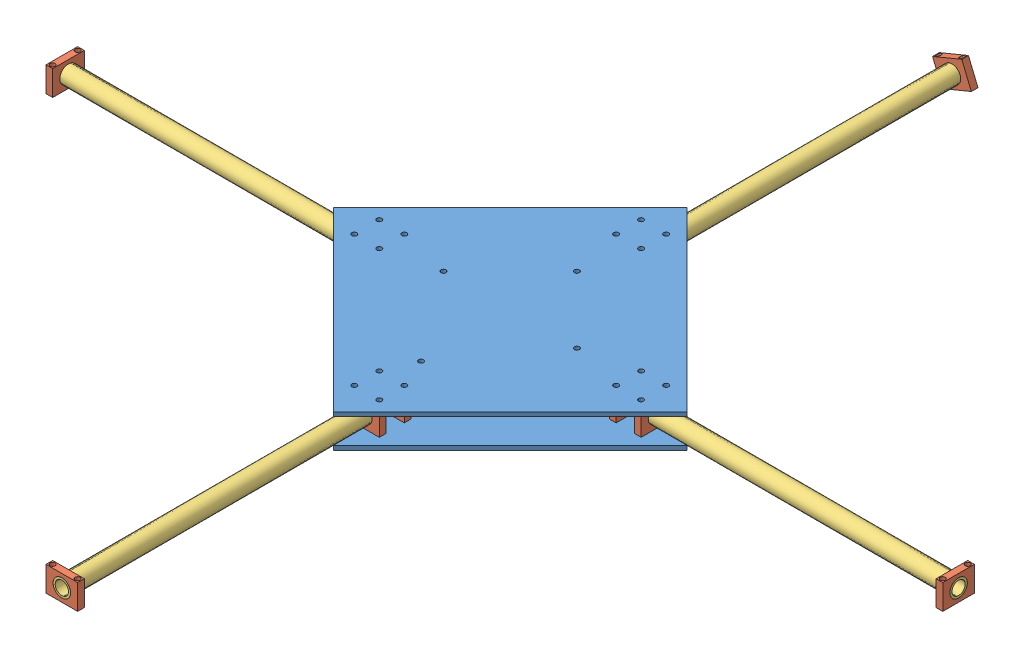
SolidWorks assembly new_drone_full_body_1, configuration Default. Lengths in mm.
Overall size (538.13 21.13 538.13).
18 component instances, 3 part files, 80 mates.
Components (placement in the parent):
- base-plate_drone_new-1: base-plate_drone_new [Default] at (-94378.7064 -1163.9739 82221.6136) size (212.13 2.5 212.15)
- holder-1: holder [Default] at (71.6083 102.2761 266.6718) x (1 0 0) z (0 1 0) size (19 4 15)
- holder-2: holder [Default] at (71.5935 87.2761 247.6718) x (1 0 0) z (0 -1 0) size (19 4 15)
- holder-4: holder [Default] at (12.0275 87.2761 169.1058) x (0 0 1) z (0 -1 0) size (19 4 15)
- holder-6: holder [Default] at (-6.9728 87.2761 188.1203) x (0.00014 0 -1) z (0 -1 0) size (19 4 15)
- holder-7: holder [Default] at (90.5787 102.2761 90.5398) x (-1 0 0) z (0 1 0) size (19 4 15)
- holder-8: holder [Default] at (71.5935 87.2761 105.5398) x (1 0 0) z (0 -1 0) size (19 4 15)
- holder-9: holder [Default] at (165.1595 102.2761 169.091) x (0 0 1) z (0 1 0) size (19 4 15)
- holder-10: holder [Default] at (150.1595 87.2761 188.1058) x (0 0 -1) z (0 -1 0) size (19 4 15)
- New_arm-1: New_arm [Default] at (350.1595 94.7761 178.6058) x (0 0 1) z (1 0 0) size (10.5 10.5 200)
- New_arm-2: New_arm [Default] at (81.0935 94.7761 109.5398) size (10.5 10.5 200)
- New_arm-3: New_arm [Default] at (12.0275 94.7761 178.6058) x (0 0.007654 -0.999971) z (1 0 0) size (10.5 10.5 200)
- New_arm-4: New_arm [Default] at (81.0935 94.7761 447.6718) size (10.5 10.5 200)
- base-plate_drone_new-2: base-plate_drone_new [Default] at (-94378.7064 -1146.4739 82221.6136) size (212.13 2.5 212.15)
- holder-11: holder [Default] at (69.4452 98.0651 -86.4602) x (0.923728 0.383049 0) z (-0.383049 0.923728 0) size (19 4 15)
- holder-12: holder [Default] at (-187.9725 102.2761 169.1058) x (0 0 1) z (0 1 0) size (19 4 15)
- holder-13: holder [Default] at (90.5935 102.2761 443.6718) x (-1 0 0) z (0 1 0) size (19 4 15)
- holder-14: holder [Default] at (346.1595 102.2761 169.1058) x (0 0 1) z (0 1 0) size (19 4 15)
Mates (geometry in assembly coordinates):
- Coincident6: coincident: circle of base-plate_drone_new-1; circle of holder-1
- Concentric1: concentric: circle of base-plate_drone_new-1; circle of holder-1
- Coincident8: coincident: circle of base-plate_drone_new-1; circle of holder-2
- Coincident9: coincident: circle of base-plate_drone_new-1; circle of holder-2
- Coincident16: coincident: circle of base-plate_drone_new-1; circle of holder-4
- Coincident17: coincident: circle of base-plate_drone_new-1; circle of holder-4
- Coincident20: coincident: circle of base-plate_drone_new-1; circle of holder-6
- Parallel2: parallel: cylinder of base-plate_drone_new-1 through (-4.9725 87.2761 171.1058) axis (0 -1 0) radius 1.5; cylinder of holder-6 through (-4.9704 102.2761 171.1206) axis (0 -1 0) radius 1.5
- Coincident22: coincident: circle of base-plate_drone_new-1; circle of holder-7
- Parallel3: parallel: cylinder of base-plate_drone_new-1 through (88.5935 87.2761 92.5398) axis (0 -1 0) radius 1.5; cylinder of holder-7 through (88.5787 87.2761 92.5398) axis (0 1 0) radius 1.5
- Coincident24: coincident: circle of base-plate_drone_new-1; circle of holder-8
- Coincident25: coincident: circle of base-plate_drone_new-1; circle of holder-8
- Coincident27: coincident: circle of base-plate_drone_new-1; circle of holder-9
- Parallel5: parallel: cylinder of base-plate_drone_new-1 through (167.1595 87.2761 186.1058) axis (0 -1 0) radius 1.5; cylinder of holder-9 through (167.1595 87.2761 186.091) axis (0 1 0) radius 1.5
- Coincident28: coincident: circle of base-plate_drone_new-1; circle of holder-10
- Coincident29: coincident: circle of base-plate_drone_new-1; circle of holder-10
- Concentric11: concentric: cylinder of holder-4 through (8.0275 94.7761 178.6058) axis (1 0 0) radius 5.25; cylinder of New_arm-3 through (-187.9725 94.7761 178.6058) axis (1 0 0) radius 5.25
- Coincident30: coincident: plane of holder-4 through (12.0275 87.2761 169.1058) normal (1 0 0); plane of New_arm-3 through (12.0275 94.7761 178.6058) normal (1 0 0)
- Concentric12: concentric: cylinder of holder-8 through (81.0935 94.7761 109.5398) axis (0 0 -1) radius 5.25; cylinder of New_arm-2 through (81.0935 94.7761 -90.4602) axis (0 0 1) radius 5.25
- Coincident31: coincident: plane of holder-8 through (71.5935 87.2761 109.5398) normal (0 0 1); plane of New_arm-2 through (81.0935 94.7761 109.5398) normal (0 0 1)
- Concentric13: concentric: cylinder of holder-2 through (81.0935 94.7761 251.6718) axis (0 0 -1) radius 5.25; cylinder of New_arm-4 through (81.0935 94.7761 247.6718) axis (0 0 1) radius 5.25
- Coincident32: coincident: plane of holder-2 through (71.5935 87.2761 247.6718) normal (0 0 -1); plane of New_arm-4 through (81.0935 94.7761 247.6718) normal (0 0 -1)
- Concentric14: concentric: cylinder of holder-10 through (154.1595 94.7761 178.6058) axis (-1 0 0) radius 5.25; cylinder of New_arm-1 through (150.1595 94.7761 178.6058) axis (1 0 0) radius 5.25
- Coincident33: coincident: plane of holder-10 through (150.1595 87.2761 188.1058) normal (-1 0 0); plane of New_arm-1 through (150.1595 94.7761 178.6058) normal (-1 0 0)
- Coincident34: coincident: circle of holder-7; circle of base-plate_drone_new-2
- Parallel6: parallel: cylinder of holder-7 through (88.5787 87.2761 92.5398) axis (0 1 0) radius 1.5; cylinder of base-plate_drone_new-2 through (88.5935 104.7761 92.5398) axis (0 -1 0) radius 1.5
- Coincident36: coincident: circle of holder-8; circle of base-plate_drone_new-2
- Parallel7: parallel: cylinder of holder-8 through (73.5935 102.2761 107.5398) axis (0 -1 0) radius 1.5; cylinder of base-plate_drone_new-2 through (73.5935 104.7761 107.5398) axis (0 -1 0) radius 1.5
- Coincident37: coincident: circle of holder-8; circle of base-plate_drone_new-2
- Parallel8: parallel: cylinder of holder-9 through (167.1595 87.2761 186.091) axis (0 1 0) radius 1.5; cylinder of base-plate_drone_new-2 through (167.1595 104.7761 186.1058) axis (0 -1 0) radius 1.5
- Parallel9: parallel: cylinder of holder-9 through (167.1595 87.2761 171.091) axis (0 1 0) radius 1.5; cylinder of base-plate_drone_new-2 through (167.1595 104.7761 171.091) axis (0 -1 0) radius 1.5
- Parallel10: parallel: cylinder of holder-10 through (152.1595 102.2761 171.1058) axis (0 -1 0) radius 1.5; cylinder of base-plate_drone_new-2 through (152.1595 104.7761 171.1058) axis (0 -1 0) radius 1.5
- Parallel11: parallel: cylinder of holder-10 through (152.1595 102.2761 186.1058) axis (0 -1 0) radius 1.5; cylinder of base-plate_drone_new-2 through (152.1595 104.7761 186.1058) axis (0 -1 0) radius 1.5
- Parallel12: parallel: cylinder of holder-1 through (88.6083 87.2761 264.6718) axis (0 1 0) radius 1.5; cylinder of base-plate_drone_new-2 through (88.6083 104.7761 264.6718) axis (0 -1 0) radius 1.5
- Parallel13: parallel: cylinder of holder-2 through (88.5935 102.2761 249.6718) axis (0 -1 0) radius 1.5; cylinder of base-plate_drone_new-2 through (88.5935 104.7761 249.6718) axis (0 -1 0) radius 1.5
- Parallel14: parallel: cylinder of holder-2 through (73.5935 102.2761 249.6718) axis (0 -1 0) radius 1.5; cylinder of base-plate_drone_new-2 through (73.5935 104.7761 249.6718) axis (0 -1 0) radius 1.5
- Parallel15: parallel: cylinder of holder-1 through (73.6083 87.2761 264.6718) axis (0 1 0) radius 1.5; cylinder of base-plate_drone_new-2 through (73.5935 104.7761 264.6718) axis (0 -1 0) radius 1.5
- Coincident40: coincident: circle of holder-4; circle of base-plate_drone_new-2
- Coincident42: coincident: circle of holder-6; circle of base-plate_drone_new-2
- Parallel19: parallel: cylinder of holder-6 through (-4.9704 102.2761 171.1206) axis (0 -1 0) radius 1.5; cylinder of base-plate_drone_new-2 through (-4.9725 104.7761 171.1058) axis (0 -1 0) radius 1.5
- Lock1: lock: unknown of holder-6; unknown of base-plate_drone_new-2
- Lock2: lock: unknown of holder-4; unknown of base-plate_drone_new-2
- Lock3: lock: unknown of holder-4; unknown of base-plate_drone_new-2
- Lock4: lock: unknown of holder-6; unknown of base-plate_drone_new-2
- Lock5: lock: unknown of holder-7; unknown of base-plate_drone_new-2
- Lock6: lock: unknown of holder-7; unknown of base-plate_drone_new-2
- Lock7: lock: unknown of holder-8; unknown of base-plate_drone_new-2
- Lock8: lock: unknown of holder-8; unknown of base-plate_drone_new-2
- Lock9: lock: unknown of base-plate_drone_new-1; unknown of holder-8
- Lock10: lock: unknown of holder-9; unknown of base-plate_drone_new-2
- Lock11: lock: unknown of base-plate_drone_new-1; unknown of holder-9
- Lock12: lock: unknown of holder-10; unknown of base-plate_drone_new-2
- Lock13: lock: unknown of base-plate_drone_new-1; unknown of holder-10
- Lock14: lock: unknown of holder-10; unknown of base-plate_drone_new-2
- Lock15: lock: unknown of base-plate_drone_new-1; unknown of holder-10
- Lock16: lock: unknown of holder-9; unknown of base-plate_drone_new-2
- Lock17: lock: unknown of base-plate_drone_new-1; unknown of holder-9
- Lock18: lock: unknown of holder-2; unknown of base-plate_drone_new-2
- Lock19: lock: unknown of base-plate_drone_new-1; unknown of holder-2
- Lock20: lock: unknown of holder-1; unknown of base-plate_drone_new-2
- Lock21: lock: unknown of base-plate_drone_new-1; unknown of holder-1
- Lock22: lock: unknown of holder-1; unknown of base-plate_drone_new-2
- Lock23: lock: unknown of base-plate_drone_new-1; unknown of holder-1
- Lock24: lock: unknown of holder-2; unknown of base-plate_drone_new-2
- Lock25: lock: unknown of base-plate_drone_new-1; unknown of holder-2
- Lock26: lock: unknown of holder-8; unknown of New_arm-2
- Lock27: lock: unknown of holder-4; unknown of New_arm-3
- Lock28: lock: unknown of holder-2; unknown of New_arm-4
- Lock29: lock: unknown of holder-10; unknown of New_arm-1
- Concentric20: concentric: cylinder of New_arm-2 through (81.0935 94.7761 -90.4602) axis (0 0 1) radius 5.25; cylinder of holder-11 through (81.0935 94.7761 -90.4602) axis (0 0 1) radius 5.25
- Lock30: lock: unknown of New_arm-2; unknown of holder-11
- Concentric21: concentric: cylinder of New_arm-3 through (-187.9725 94.7761 178.6058) axis (1 0 0) radius 5.25; cylinder of holder-12 through (-183.9725 94.7761 178.6058) axis (-1 0 0) radius 5.25
- Coincident51: coincident: plane of New_arm-3 through (-187.9725 94.7761 178.6058) normal (-1 0 0); plane of holder-12 through (-187.9725 102.2761 169.1058) normal (-1 0 0)
- Lock32: lock: unknown of New_arm-3; unknown of holder-12
- Concentric22: concentric: cylinder of New_arm-4 through (81.0935 94.7761 247.6718) axis (0 0 1) radius 5.25; cylinder of holder-13 through (81.0935 94.7761 447.6718) axis (0 0 -1) radius 5.25
- Coincident52: coincident: plane of New_arm-4 through (81.0935 94.7761 447.6718) normal (0 0 1); plane of holder-13 through (90.5935 102.2761 447.6718) normal (0 0 1)
- Lock33: lock: unknown of New_arm-4; unknown of holder-13
- Concentric23: concentric: cylinder of New_arm-1 through (150.1595 94.7761 178.6058) axis (1 0 0) radius 5.25; cylinder of holder-14 through (350.1595 94.7761 178.6058) axis (-1 0 0) radius 5.25
- Coincident54: coincident: plane of New_arm-1 through (350.1595 94.7761 178.6058) normal (1 0 0); plane of holder-14 through (350.1595 102.2761 169.1058) normal (1 0 0)
- Lock34: lock: unknown of New_arm-1; unknown of holder-14
